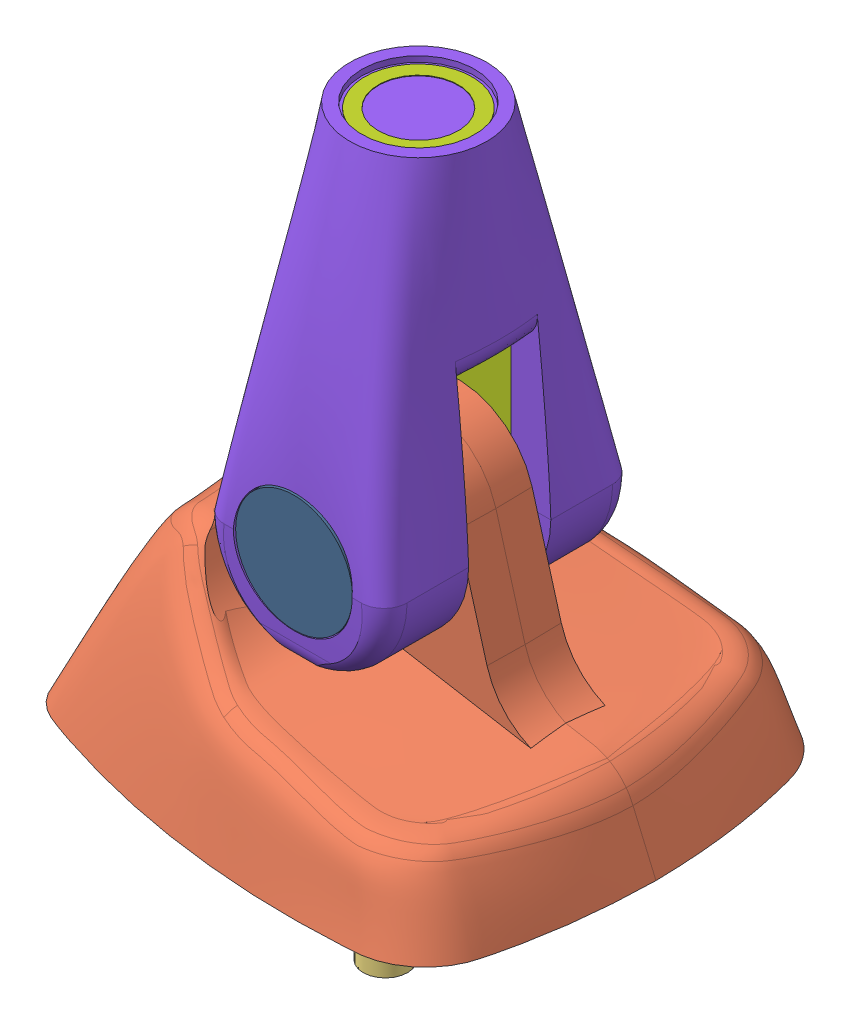
SolidWorks assembly Assem, configuration Default. Lengths in mm.
Overall size (42.09 66.7 37.33).
12 component instances, 11 part files, 14 mates.
Components (placement in the parent):
- rv2base metal-1: rv2base metal [Default] at (-19.3424 -0.4283 1.3444) size (26 20 16.8)
- rv2base_plastic_4-1: rv2base_plastic_4 [Default] at (-15.3768 -3.8158 1.3444) x (-1 0 0) z (0 -1 0) size (42533.26 37922.71 43425.84)
- rv2BaseScrew-1: rv2BaseScrew [Default] at (-19.3276 1.1717 1.3444) x (0.876079 0 0.482167) z (-0.482167 0 0.876079) size (10.39 25.7 9)
- rv2ThinMetalWasher-1: rv2ThinMetalWasher [Default] at (-16.2424 14.0717 4.4888) size (11 11 1.3)
- rv2ThickMetalWasher-1: rv2ThickMetalWasher [Default] at (-16.2424 14.0717 -2.0056) size (11 11 1.1)
- rv2Up Assem-1: rv2Up Assem [Default] at (-16.2059 -27.3657 27.5758) x (1 0 0) z (0 -1 0) size (16 22.68 37.51)
  - rv2screw pin-1: rv2screw pin [Default] at (-0.0364 -18.95 -41.4374) size (7.4 17.5 7.4)
  - rv2top metal-1: rv2top metal [Default] at (-0.0364 -26.0313 -70.4902) x (1 0 0) z (0 -1 0) size (12.6 35.36 14.81)
  - rv2upper part2-1: rv2upper part2 [Default] at (-0.0364 -26.0313 -70.9374) x (0 1 0) z (1 0 0) size (22.68 37.51 16)
  - rv2screw pin spacer-1: rv2screw pin spacer [Default] at (-0.0364 -22.7 -41.4374) x (0 0 1) z (-1 0 0) size (8.08 3.75 7)
  - rv2screw cover-1: rv2screw cover [Default] at (-0.0364 -18.95 -41.4374) size (10.3 3.8 10.3)
- rv2washer-1: rv2washer [Default] at (-19.3276 -0.4258 1.3444) x (0 0 1) z (1 0 0) size (21 4 21)
Mates (geometry in assembly coordinates):
- Concentric1: concentric anti-aligned: circle of rv2base_plastic_4-1; circle of rv2base metal-1
- Distance2: distance = 1 mm aligned: plane of rv2base_plastic_4-1 through (-15.3768 -3.8158 4.5944) normal (0 0 1); plane of rv2base metal-1 through (-19.3424 -0.4283 3.5944) normal (0 0 1)
- Concentric3: concentric aligned: cylinder of rv2base_plastic_4-1 through (-19.3276 -7.9258 1.3444) axis (0 1 0) radius 2.75; cylinder of rv2BaseScrew-1 through (-19.3276 -23.1283 1.3444) axis (0 1 0) radius 2.425
- Parallel1: parallel anti-aligned: plane of rv2base metal-1 through (-14.5851 1.0217 1.247) normal (-0.99979 0 0.020471); plane of rv2BaseScrew-1 through (-14.7764 2.5717 3.8493) normal (0.99979 0 -0.020471)
- Coincident3: coincident anti-aligned: plane of rv2base metal-1 through (-19.3424 2.5717 1.3444) normal (0 -1 0); plane of rv2BaseScrew-1 through (-19.3276 2.5717 1.3444) normal (0 1 0)
- Concentric4: concentric anti-aligned: cylinder of rv2ThickMetalWasher-1 through (-16.2424 14.0717 -0.9056) axis (0 0 -1) radius 2.6; circle of rv2Up Assem-1/rv2upper part2-1
- Coincident4: coincident anti-aligned: plane of rv2base metal-1 through (-19.3424 -0.4283 -0.9056) normal (0 0 -1); plane of rv2ThickMetalWasher-1 through (-16.2424 14.0717 -0.9056) normal (0 0 1)
- Concentric5: concentric aligned: circle of rv2ThinMetalWasher-1; circle of rv2Up Assem-1/rv2upper part2-1
- Coincident5: coincident aligned: plane of rv2base metal-1 through (-19.3424 -0.4283 3.5944) normal (0 0 1); circle of rv2ThinMetalWasher-1
- Concentric6: concentric aligned: cylinder of rv2Up Assem-1/rv2screw pin-1 through (-16.2424 14.0717 -6.3742) axis (0 0 1) radius 2.45; circle of rv2base metal-1
- Distance4: distance = 3.55 mm aligned: plane of rv2ThickMetalWasher-1 through (-16.2424 14.0717 -2.0056) normal (0 0 -1); plane of rv2Up Assem-1/rv2top metal-1 through (-16.2424 43.1245 1.5444) normal (0 0 -1)
- Coincident7: coincident anti-aligned: plane of rv2washer-1 through (-19.3276 -0.4258 1.3444) normal (0 1 0); plane of rv2base_plastic_4-1 through (-15.3768 -0.4258 1.3444) normal (0 -1 0)
- Parallel3: parallel aligned: plane of rv2base metal-1 through (-19.3424 -0.4283 1.3444) normal (0 0 1); plane of rv2washer-1
- Concentric10: concentric aligned: circle of rv2washer-1; circle of rv2base_plastic_4-1
